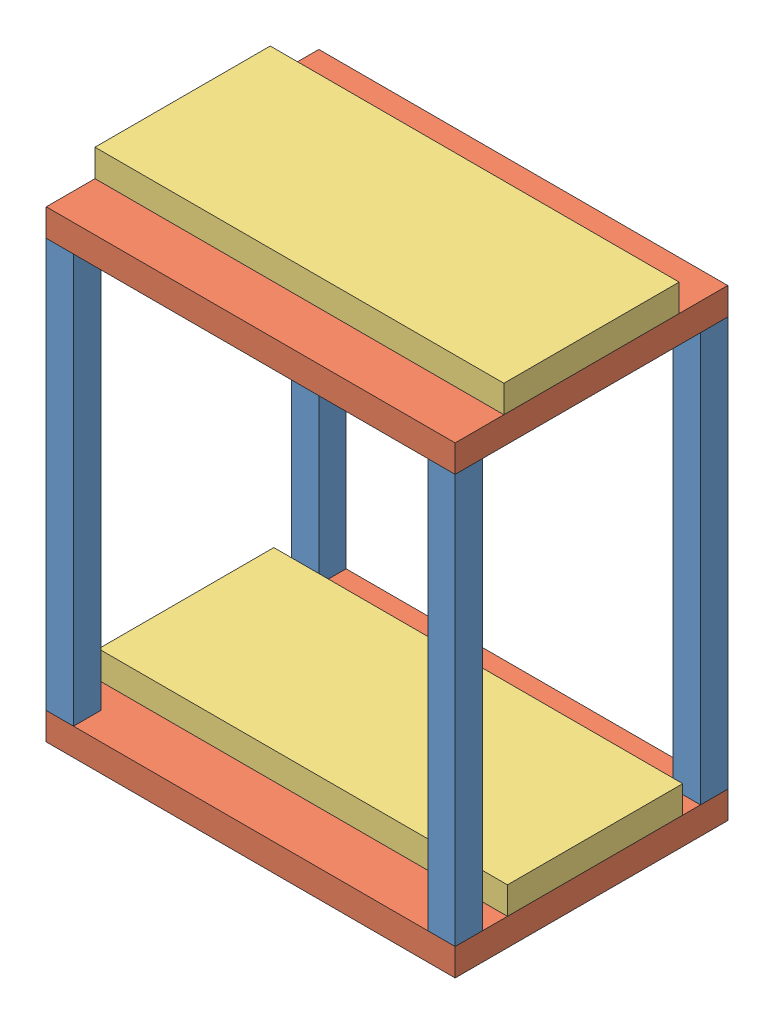
SolidWorks assembly modèle rigide, configuration Défaut. Lengths in mm.
Overall size (150 180 100).
8 component instances, 3 part files, 20 mates.
Components (placement in the parent):
- baguette-1: baguette [Défaut] at (-75.0128 12.4171 105) size (10 150 10)
- base-1: base [Défaut] at (-75.0128 2.4171 195) size (150 10 100)
- base-2: base [Défaut] at (-75.0128 162.4171 195) size (150 10 100)
- baguette-2: baguette [Défaut] at (-75.0128 12.4171 195) size (10 150 10)
- baguette-3: baguette [Défaut] at (64.9872 12.4171 105) size (10 150 10)
- baguette-4: baguette [Défaut] at (64.9872 12.4171 195) size (10 150 10)
- téléphone-1: téléphone [Défaut] at (-75.0128 12.4171 175.8047) size (150 10 64.29)
- téléphone-2: téléphone [Défaut] at (-75.0128 172.4171 177.1213) size (150 10 64.29)
Mates (geometry in assembly coordinates):
- Coïncidente1: coincident anti-aligned: plane of baguette-1 through (-75.0128 12.4171 105) normal (0 -1 0); plane of base-1 through (-75.0128 12.4171 195) normal (0 1 0)
- Coïncidente2: coincident aligned: plane of baguette-1 through (-75.0128 162.4171 105) normal (-1 0 0); plane of base-1 through (-75.0128 12.4171 195) normal (-1 0 0)
- Coïncidente3: coincident aligned: plane of baguette-1 through (-75.0128 162.4171 95) normal (0 0 -1); plane of base-1 through (-75.0128 12.4171 95) normal (0 0 -1)
- Coïncidente4: coincident aligned: plane of base-1 through (-75.0128 12.4171 195) normal (-1 0 0); plane of baguette-2 through (-75.0128 162.4171 195) normal (-1 0 0)
- Coïncidente5: coincident aligned: plane of base-1 through (-75.0128 12.4171 195) normal (0 0 1); plane of baguette-2 through (-75.0128 162.4171 195) normal (0 0 1)
- Coïncidente6: coincident anti-aligned: plane of base-1 through (-75.0128 12.4171 195) normal (0 1 0); plane of baguette-2 through (-75.0128 12.4171 195) normal (0 -1 0)
- Coïncidente7: coincident anti-aligned: plane of base-1 through (-75.0128 12.4171 195) normal (0 1 0); plane of baguette-3 through (64.9872 12.4171 105) normal (0 -1 0)
- Coïncidente8: coincident aligned: plane of base-1 through (-75.0128 12.4171 95) normal (0 0 -1); plane of baguette-3 through (64.9872 162.4171 95) normal (0 0 -1)
- Coïncidente9: coincident aligned: plane of base-1 through (74.9872 12.4171 195) normal (1 0 0); plane of baguette-3 through (74.9872 162.4171 105) normal (1 0 0)
- Coïncidente10: coincident aligned: plane of base-1 through (74.9872 12.4171 195) normal (1 0 0); plane of baguette-4 through (74.9872 162.4171 195) normal (1 0 0)
- Coïncidente11: coincident anti-aligned: plane of base-1 through (-75.0128 12.4171 195) normal (0 1 0); plane of baguette-4 through (64.9872 12.4171 195) normal (0 -1 0)
- Coïncidente12: coincident: line of base-1 through (-75.0128 12.4171 195) axis (1 0 0); plane of baguette-4 through (64.9872 162.4171 195) normal (0 0 1)
- Coïncidente13: coincident anti-aligned: plane of base-2 through (-75.0128 162.4171 195) normal (0 -1 0); plane of baguette-4 through (64.9872 162.4171 195) normal (0 1 0)
- Coïncidente15: coincident aligned: plane of base-2 through (-75.0128 172.4171 195) normal (-1 0 0); plane of baguette-2 through (-75.0128 162.4171 195) normal (-1 0 0)
- Coïncidente16: coincident aligned: plane of base-2 through (-75.0128 172.4171 195) normal (0 0 1); plane of baguette-2 through (-75.0128 162.4171 195) normal (0 0 1)
- Coïncidente17: coincident anti-aligned: plane of base-1 through (-75.0128 12.4171 195) normal (0 1 0); plane of téléphone-1 through (-75.0128 12.4171 175.8047) normal (0 -1 0)
- Parallèle2: parallel anti-aligned: plane of base-1 through (-75.0128 12.4171 195) normal (0 1 0); plane of téléphone-1 through (-75.0128 12.4171 175.8047) normal (0 -1 0)
- Coïncidente20: coincident aligned: plane of base-1 through (-75.0128 12.4171 195) normal (-1 0 0); plane of téléphone-1 through (-75.0128 22.4171 175.8047) normal (-1 0 0)
- Coïncidente21: coincident anti-aligned: plane of base-2 through (-75.0128 172.4171 195) normal (0 1 0); plane of téléphone-2 through (-75.0128 172.4171 177.1213) normal (0 -1 0)
- Coïncidente22: coincident aligned: plane of base-2 through (-75.0128 172.4171 195) normal (-1 0 0); plane of téléphone-2 through (-75.0128 182.4171 177.1213) normal (-1 0 0)
